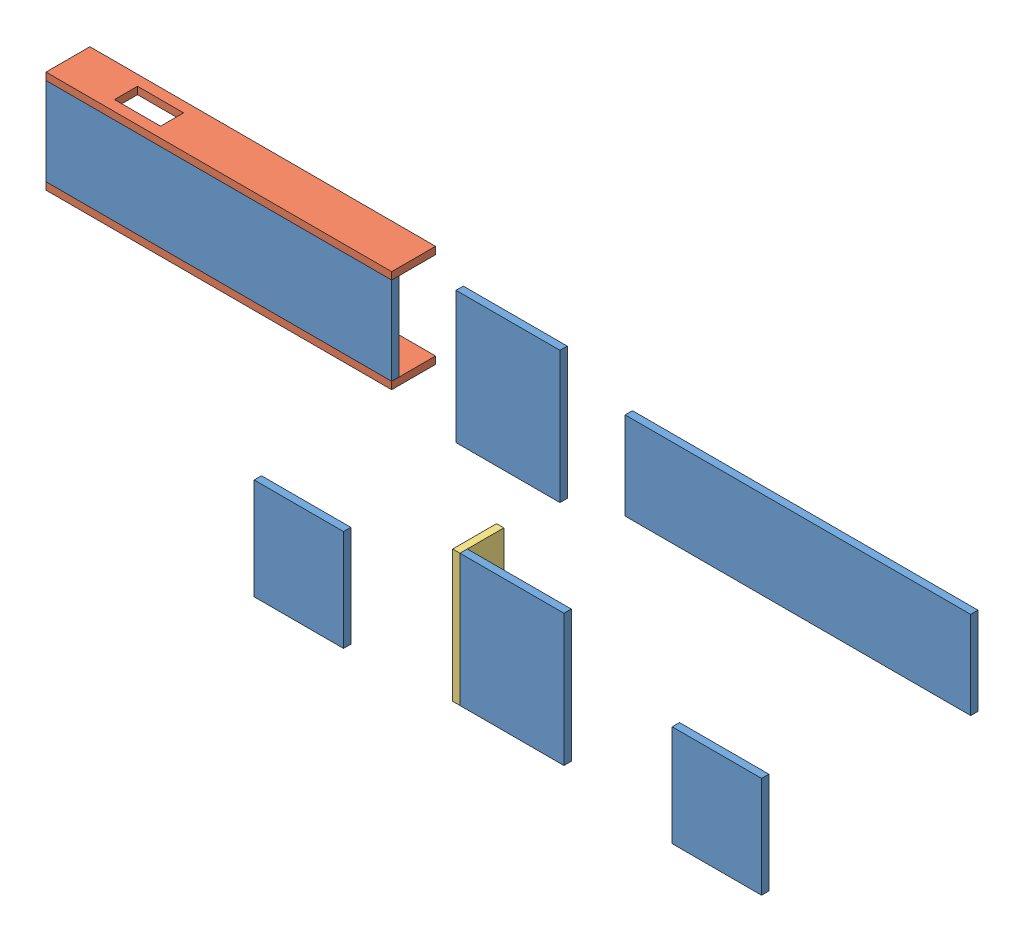
SolidWorks assembly operant box cable management, configuration Default. Lengths in mm.
Overall size (802.8 322.23 38.1).
5 component instances, 4 part files, 11 mates.
Components (placement in the parent):
- Structural_base_TotalAssembly_V3-1: Structural_base_TotalAssembly_V3 [Default] at origin size (802.8 322.23 6.35)
- Part3^operant box cable management-1: Part3^operant box cable management [Default] at origin (virtual)
- structural_base_A_side-1: structural_base_A_side [Default] x (-1 0 0) z (0 0 -1) size (300.1 6.35 38.1)
- structural_base_A_side-2: structural_base_A_side [Default] at (0 16.5519 -25.4) x (-1 0 0) z (0 0 1) size (300.1 6.35 38.1)
- Part7^operant box cable management-1: Part7^operant box cable management [Default] at (-36.0278 0 0) x (0 0 1) z (-1 0 0) size (38.1 114.52 6.35) (virtual)
Mates (geometry in assembly coordinates):
- InPlace1: in place: plane of ? through (0 0 0) normal (0 0 -1); plane of structural_base_A_side-1 through (0 0 0) normal (0 0 -1); moOrthogonalPlaneRef_w of ? through (0 0 0) normal (0 0 -1); plane of structural_base_A_side-1 through (0 0 0) normal (0 1 0); plane of ? through (0 0 0) normal (0 0 -1); plane of structural_base_A_side-1 through (0 0 0) normal (-1 0 0); plane of ? through (0 0 0) normal (0 0 -1); unknown of structural_base_A_side-1
- Coincident1: coincident aligned: plane of ?; plane of ?
- Coincident2: coincident aligned: moOrthogonalPlaneRef_w of Structural_base_TotalAssembly_V3-1 through (0 0 0) normal (0 1 0); plane of Part4^Assem2-1 through (0 0 0) normal (0 1 0)
- Coincident3: coincident anti-aligned: moOrthogonalPlaneRef_w of Structural_base_TotalAssembly_V3-1 through (0 0 0) normal (1 0 0); plane of Part4^Assem2-1 through (0 0 0) normal (-1 0 0)
- Coincident7: coincident anti-aligned: plane of Structural_base_TotalAssembly_V3-1 through (-95.4432 -29.7782 6.35) normal (0 -1 0); plane of structural_base_A_side-2 through (-395.4432 -29.7782 6.35) normal (0 1 0)
- Coincident8: coincident aligned: plane of Structural_base_TotalAssembly_V3-1 through (-395.4432 -29.7782 6.35) normal (-1 0 0); plane of structural_base_A_side-2 through (-395.4432 -29.7782 6.35) normal (-1 0 0)
- Coincident9: coincident aligned: plane of Structural_base_TotalAssembly_V3-1 through (0 0 6.35) normal (0 0 1); plane of structural_base_A_side-2 through (0 16.5519 6.35) normal (0 0 1)
- InPlace4: in place: plane of ? through (-36.0278 -243.8934 6.35) normal (-1 0 0); plane of Part7^operant box cable management-1 through (-36.0278 0 0) normal (-1 0 0); plane of ? through (-36.0278 -243.8934 6.35) normal (-1 0 0); plane of Part7^operant box cable management-1 through (-36.0278 0 0) normal (0 1 0); plane of ? through (-36.0278 -243.8934 6.35) normal (-1 0 0); plane of Part7^operant box cable management-1 through (-36.0278 0 0) normal (0 0 1); plane of ? through (-36.0278 -243.8934 6.35) normal (-1 0 0); unknown of Part7^operant box cable management-1
- Coincident16: coincident aligned: plane of ?; plane of ?
- Coincident17: coincident aligned: moOrthogonalPlaneRef_w of Structural_base_TotalAssembly_V3-1 through (-36.0278 0 0) normal (0 1 0); plane of Part7^Assem2-1 through (-36.0278 0 0) normal (0 1 0)
- Coincident18: coincident anti-aligned: moOrthogonalPlaneRef_w of Structural_base_TotalAssembly_V3-1 through (-36.0278 0 0) normal (0 0 -1); plane of Part7^Assem2-1 through (-36.0278 0 0) normal (0 0 1)
